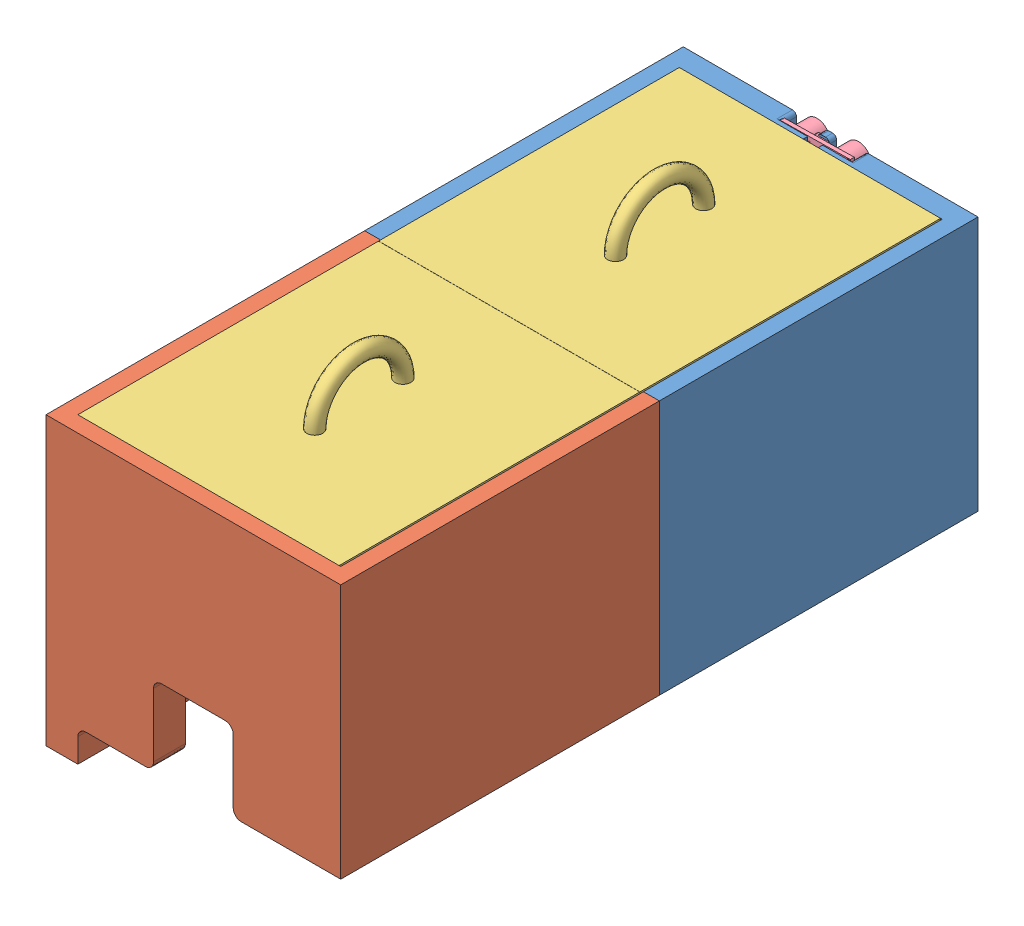
SolidWorks assembly aprojector cover assembly, configuration Default. Lengths in mm.
Overall size (185 212.67 405.5).
5 component instances, 4 part files, 11 mates.
Components (placement in the parent):
- aprojector front frame-1: aprojector front frame [Default] at (55.1557 121.5852 168.6) size (185 180 212.5)
- aprojector back frame-1: aprojector back frame [Default] at (240.1557 121.5852 568.6) x (-1 0 0) z (0 0 -1) size (185 180 200)
- aprojector lid-1: aprojector lid [Default] at (65.1557 269.0852 181.1) x (0 0 1) z (0 1 0) size (188.7 164 45.17)
- aprojector lid-2: aprojector lid [Default] at (65.1557 269.0852 369.9) x (0 0 1) z (0 1 0) size (188.7 164 45.17)
- Ultrasonic sensor-1: Ultrasonic sensor [Default] at (146.6655 271.3951 177.5968) x (-0.999893 -0.014623 0) z (0 0 -1) size (45 25.46 18.5)
Mates (geometry in assembly coordinates):
- Parallel1: parallel: plane of aprojector front frame-1 through (55.1557 121.5852 368.6) normal (0 0 1); plane of aprojector back frame-1 through (240.1557 121.5852 368.6) normal (0 0 -1)
- Coincident2: coincident: plane of aprojector front frame-1 through (55.1557 121.5852 368.6) normal (0 0 1); plane of aprojector back frame-1 through (240.1557 121.5852 368.6) normal (0 0 -1)
- Coincident3: coincident: line of aprojector front frame-1 through (75.1557 101.5852 368.6) axis (-1 0 0); line of aprojector back frame-1 through (55.1557 101.5852 368.6) axis (1 0 0)
- Coincident4: coincident: line of aprojector front frame-1 through (55.1557 281.5852 368.6) axis (0 -1 0); line of aprojector back frame-1 through (55.1557 101.5852 368.6) axis (0 1 0)
- Coincident5: coincident: plane of aprojector front frame-1 through (65.1557 269.0852 368.6) normal (1 0 0); plane of aprojector lid-1 through (65.1557 281.5852 181.1) normal (-1 0 0)
- Coincident6: coincident: plane of aprojector front frame-1 through (230.1557 269.0852 181.1) normal (0 0 1); plane of aprojector lid-1 through (65.1557 281.5852 181.1) normal (0 0 -1)
- Coincident7: coincident: plane of aprojector front frame-1 through (55.1557 281.5852 193.6) normal (0 1 0); plane of aprojector lid-1 through (65.1557 281.5852 181.1) normal (0 1 0)
- Coincident8: coincident: plane of aprojector back frame-1 through (65.1557 269.0852 368.6) normal (1 0 0); plane of aprojector lid-2 through (65.1557 281.5852 369.9) normal (-1 0 0)
- Coincident9: coincident: plane of aprojector back frame-1 through (230.1557 269.0852 558.6) normal (0 0 -1); plane of aprojector lid-2 through (65.1557 281.5852 558.6) normal (0 0 1)
- Coincident10: coincident: line of aprojector back frame-1 through (55.1557 281.5852 568.6) axis (1 0 0); plane of aprojector lid-2 through (65.1557 281.5852 369.9) normal (0 1 0)
- Concentric1: concentric: cylinder of aprojector front frame-1 through (159.6641 271.5852 168.6) axis (0 0 1) radius 8.25; cylinder of Ultrasonic sensor-1 through (159.6641 271.5852 163.0968) axis (0 0 1) radius 8
